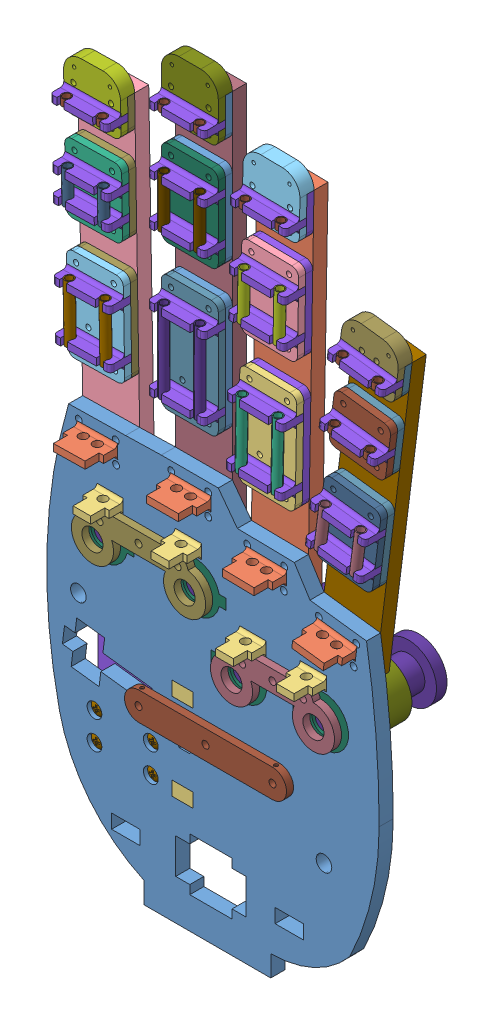
SolidWorks assembly palmUpComplete_Whiffletree, configuration Default. Lengths in mm.
Overall size (100.53 213.84 40.29).
205 component instances, 52 part files, 124 mates.
Components (placement in the parent):
- palmUp-1: palmUp [Default] at (29.1174 30.4931 80.2216) size (94.52 113.2 4)
- driverBaseFrame1-1: driverBaseFrame1 [Default] at (-2.9175 115.1932 80.2216) x (0.999847 0.017467 0) z (0.017467 -0.999847 0) size (11.5 12 4)
- driverBaseFrame1-2: driverBaseFrame1 [Default] at (23.5924 115.6931 80.2216) x (1 0 0) z (0 -1 0) size (11.5 12 4)
- driverBaseFrame1-3: driverBaseFrame1 [Default] at (45.1535 108.3901 80.2216) x (0.999848 -0.017452 0) z (-0.017452 -0.999848 0) size (11.5 12 4)
- driverBaseFrame1-4: driverBaseFrame1 [Default] at (65.1211 100.8452 80.2216) x (0.992117 -0.125312 0) z (-0.125312 -0.992117 0) size (11.5 12 4)
- driverBaseFrame2-1: driverBaseFrame2 [Default] at (-1948.2383 102.6443 -1374.6625) x (1 0 0) z (0 -1 0) size (7.5 12 4)
- driverBaseFrame2-2: driverBaseFrame2 [Default] at (1983.3157 100.6443 -1374.6625) x (-1 0 0) z (0 1 0) size (7.5 12 4)
- driverBaseFrame2-4: driverBaseFrame2 [Default] at (-1907.6963 87.8147 -1374.6625) x (1 0 0) z (0 -1 0) size (7.5 12 4)
- driverBaseFrame2-5: driverBaseFrame2 [Default] at (-1890.412 87.8147 -1374.6625) x (1 0 0) z (0 -1 0) size (7.5 12 4)
- index-1: index [Default] at (-52.494 173.2306 -0.0096) x (-0.999847 -0.017467 0) z (0 0 -1) size (16.2 99.16 12.01)
  - indexElastomer-1: indexElastomer [Default] at (-62.4059 -67.241 -80.2312) size (16.2 94.16 4)
  - indexPIP-1: indexPIP [Default] at (-62.4059 -42.8945 -84.2312) size (16.2 26.26 2)
  - indexMIP-1: indexMIP [Default] at (-62.4059 -8.6345 -84.2312) size (16.2 19.45 2)
  - indexDIP-1: indexDIP [Default] at (-62.4059 16.8205 -84.2312) size (16.2 14.95 4)
  - tubeDriver-6: tubeDriver [Default] at (-62.4059 20.8205 -80.2312) x (1 0 0) z (0 1 0) size (16.2 6 4)
  - tubeDriver-7: tubeDriver [Default] at (-62.4059 3.8205 -80.2312) x (1 0 0) z (0 1 0) size (16.2 6 4)
  - tubeDriver-8: tubeDriver [Default] at (-62.4059 -3.6345 -80.2312) x (1 0 0) z (0 1 0) size (16.2 6 4)
  - tubeDriver-9: tubeDriver [Default] at (-62.4059 -23.6345 -80.2312) x (1 0 0) z (0 1 0) size (16.2 6 4)
  - tubeDriver-10: tubeDriver [Default] at (-62.4059 -37.8945 -80.2312) x (1 0 0) z (0 1 0) size (16.2 6 4)
  - indexTube1-1: indexTube1 [Default] at (-49.2059 -21.6345 -86.4812) x (-0.964902 0 0.26261) z (0 -1 0) size (2.5 2.5 16.26)
  - indexTube1-2: indexTube1 [Default] at (-59.4059 -21.6345 -86.4812) x (-0.775159 0 0.631766) z (0 -1 0) size (2.5 2.5 16.26)
  - indexTube2-1: indexTube2 [Default] at (-49.2059 5.8205 -86.4812) x (0.360054 0 0.932932) z (0 -1 0) size (2.5 2.5 9.46)
  - indexTube2-2: indexTube2 [Default] at (-59.4059 5.8205 -86.4812) x (-0.658969 0 -0.75217) z (0 -1 0) size (2.5 2.5 9.46)
  - commonFingersTube-1: commonFingersTube [Default] at (-49.2059 22.8205 -86.4812) x (-0.856421 0 0.516277) z (0 -1 0) size (2.5 2.5 2)
  - commonFingersTube-2: commonFingersTube [Default] at (-59.4059 22.8205 -86.4812) x (-0.999231 0 0.039215) z (0 -1 0) size (2.5 2.5 2)
  - indexJointBase-1: indexJointBase [Default] at (-62.4059 -67.241 -82.2312) size (16.2 69.66 2)
- middle-1: middle [Default] at (34.8412 175.8995 -30.6566) size (16.2 113.14 12)
  - middleElastomer-1: middleElastomer [Default] at (-13.8237 -68.7065 106.8781) size (16.2 108.14 4)
  - middlePIP-1: middlePIP [Default] at (-13.8237 -44.2065 110.8781) size (16.2 33.21 2)
  - middleMIP-1: middleMIP [Default] at (-13.8237 -2.9965 110.8781) size (16.2 24.45 2)
  - middleDIP-1: middleDIP [Default] at (-5.7237 27.4535 110.8781) size (16.2 16.98 4)
  - tubeDriver-2: tubeDriver [Default] at (-13.8237 33.4535 110.8781) x (1 0 0) z (0 -1 0) size (16.2 6 4)
  - tubeDriver-3: tubeDriver [Default] at (-13.8237 16.4535 110.8781) x (1 0 0) z (0 -1 0) size (16.2 6 4)
  - tubeDriver-4: tubeDriver [Default] at (-13.8237 4.0035 110.8781) x (1 0 0) z (0 -1 0) size (16.2 6 4)
  - tubeDriver-5: tubeDriver [Default] at (-13.8237 -15.9965 110.8781) x (1 0 0) z (0 -1 0) size (16.2 6 4)
  - tubeDriver-6: tubeDriver [Default] at (-13.8237 -37.2065 110.8781) x (1 0 0) z (0 -1 0) size (16.2 6 4)
  - middleTube1-1: middleTube1 [Default] at (-10.8237 -39.2065 117.1281) x (1 0 0) z (0 1 0) size (2.5 2.5 23.21)
  - middleTube1-2: middleTube1 [Default] at (-0.6237 -39.2065 117.1281) x (1 0 0) z (0 1 0) size (2.5 2.5 23.21)
  - middleTube2-1: middleTube2 [Default] at (-10.8237 2.0035 117.1281) x (1 0 0) z (0 1 0) size (2.5 2.5 14.45)
  - middleTube2-2: middleTube2 [Default] at (-0.6237 2.0035 117.1281) x (1 0 0) z (0 1 0) size (2.5 2.5 14.45)
  - commonFingersTube-1: commonFingersTube [Default] at (-10.8237 31.4535 117.1281) x (1 0 0) z (0 1 0) size (2.5 2.5 2)
  - commonFingersTube-2: commonFingersTube [Default] at (-0.6237 31.4535 117.1281) x (1 0 0) z (0 1 0) size (2.5 2.5 2)
  - middleJointBase-1: middleJointBase [Default] at (-13.8237 -70.2065 110.8781) size (16.2 83.64 2)
- ring-1: ring [Default] at (23.5555 139.8292 -20.9472) x (-0.999848 0.017452 0) z (0 0 -1) size (16.2 107.96 12)
  - ringElastomer-1: ringElastomer [Default] at (-35.7683 -39.5573 -101.1688) size (16.2 102.96 4)
  - ringPIP-1: ringPIP [Default] at (-35.7683 -15.0573 -105.1688) size (16.2 29.14 2)
  - ringMIP-1: ringMIP [Default] at (-35.7683 22.0827 -105.1688) size (16.2 23.53 2)
  - ringDIP-1: ringDIP [Default] at (-19.5683 51.6077 -101.1688) x (-1 0 0) z (0 0 -1) size (16.2 16.8 4)
  - tubeDriver-6: tubeDriver [Default] at (-35.7683 55.6077 -101.1688) x (1 0 0) z (0 1 0) size (16.2 6 4)
  - tubeDriver-7: tubeDriver [Default] at (-35.7683 38.6077 -101.1688) x (1 0 0) z (0 1 0) size (16.2 6 4)
  - tubeDriver-8: tubeDriver [Default] at (-35.7683 27.0827 -101.1688) x (1 0 0) z (0 1 0) size (16.2 6 4)
  - tubeDriver-9: tubeDriver [Default] at (-35.7683 7.0827 -101.1688) x (1 0 0) z (0 1 0) size (16.2 6 4)
  - tubeDriver-10: tubeDriver [Default] at (-35.7683 -10.0573 -101.1688) x (1 0 0) z (0 1 0) size (16.2 6 4)
  - ringTube1-1: ringTube1 [Default] at (-22.5683 9.0827 -107.4188) x (1 0 0) z (0 -1 0) size (2.5 2.5 19.14)
  - ringTube1-2: ringTube1 [Default] at (-32.7683 9.0827 -107.4188) x (1 0 0) z (0 -1 0) size (2.5 2.5 19.14)
  - ringTube2-1: ringTube2 [Default] at (-22.5683 40.6077 -107.4188) x (1 0 0) z (0 -1 0) size (2.5 2.5 13.53)
  - ringTube2-2: ringTube2 [Default] at (-32.7683 40.6077 -107.4188) x (1 0 0) z (0 -1 0) size (2.5 2.5 13.53)
  - commonFingersTube-1: commonFingersTube [Default] at (-22.5683 57.6077 -107.4188) x (1 0 0) z (0 -1 0) size (2.5 2.5 2)
  - commonFingersTube-2: commonFingersTube [Default] at (-32.7683 57.6077 -107.4188) x (-0.448476 0 -0.893795) z (0 -1 0) size (2.5 2.5 2)
  - ringJointBase-1: ringJointBase [Default] at (-35.7683 -41.0573 -103.1688) size (16.2 78.46 2)
- pinky-1: pinky [Default] at (76.9532 164.3008 -0.0182) x (0.992117 -0.125312 0) z (0 0 1) size (16.2 89.09 12)
  - pinkyElastomer-1: pinkyElastomer [Default] at (-6.1366 -72.9381 76.2397) size (16.2 84.09 4)
  - pinkyPIP-1: pinkyPIP [Default] at (-6.1366 -48.4381 80.2397) size (16.2 21.74 2)
  - pinkyMIP-1: pinkyMIP [Default] at (-6.1366 -18.6981 80.2397) size (16.2 14.64 2)
  - pinkyDIP-1: pinkyDIP [Default] at (-6.1366 1.9469 80.2397) size (16.2 14.21 4)
  - tubeDriver-5: tubeDriver [Default] at (-6.1366 7.9469 80.2397) x (1 0 0) z (0 -1 0) size (16.2 6 4)
  - tubeDriver-7: tubeDriver [Default] at (-6.1366 -31.6981 80.2397) x (1 0 0) z (0 -1 0) size (16.2 6 4)
  - tubeDriver-8: tubeDriver [Default] at (-6.1366 -41.4381 80.2397) x (1 0 0) z (0 -1 0) size (16.2 6 4)
  - pinkyTube1-1: pinkyTube1 [Default] at (-3.1366 -43.4381 86.4897) x (1 0 0) z (0 1 0) size (2.5 2.5 11.74)
  - pinkyTube1-2: pinkyTube1 [Default] at (7.0634 -43.4381 86.4897) x (1 0 0) z (0 1 0) size (2.5 2.5 11.74)
  - tubeDriver-10: tubeDriver [Default] at (-6.1366 -10.3756 80.2397) x (1 0 0) z (0 -1 0) size (16.2 6 4)
  - commonFingersTube-1: commonFingersTube [Default] at (-3.1366 5.9469 86.4897) x (1 0 0) z (0 1 0) size (2.5 2.5 2)
  - commonFingersTube-2: commonFingersTube [Default] at (7.0634 5.9469 86.4897) x (1 0 0) z (0 1 0) size (2.5 2.5 2)
  - pinkyJointBase-1: pinkyJointBase [Default] at (-6.1366 -74.4381 80.2397) size (16.2 59.59 2)
  - commonFingersTube-3: commonFingersTube [Default] at (-3.1366 -12.3756 86.4897) x (1 0 0) z (0 1 0) size (2.5 2.5 2)
  - commonFingersTube-4: commonFingersTube [Default] at (7.0634 -12.3756 86.4897) x (1 0 0) z (0 1 0) size (2.5 2.5 2)
- buttonBase-1: buttonBase [Default] at (67.2648 77.3147 84.2216) x (0 -1 0) z (0 0 -1) size (16 16.84 9)
- buttonBase-2: buttonBase [Default] at (43.9805 77.3147 84.2216) x (0 -1 0) z (0 0 -1) size (16 16.84 9)
- buttonBase-3: buttonBase [Default] at (30.6388 92.1443 84.2216) x (0 1 0) z (0 0 -1) size (16 16.84 9)
- buttonBase-4: buttonBase [Default] at (4.4385 92.1443 84.2216) x (0 1 0) z (0 0 -1) size (16 16.84 9)
- buttonFrame-1: buttonFrame [Default] at (67.2648 77.3147 67.2216) x (-0.367754 -0.929923 0) z (0 0 1) size (16 16 8)
- buttonFrame-2: buttonFrame [Default] at (43.9805 77.3147 67.2216) x (-0.367754 -0.929923 0) z (0 0 1) size (16 16 8)
- buttonFrame-3: buttonFrame [Default] at (4.4385 92.1443 67.2216) x (-0.366273 -0.930508 0) z (0 0 1) size (16 16 8)
- buttonFrame-4: buttonFrame [Default] at (30.6388 92.1443 67.2216) x (-0.366273 -0.930508 0) z (0 0 1) size (16 16 8)
- buttonAxle-1: buttonAxle [Default] at (67.2648 77.3147 57.2216) size (16 16 27)
- buttonAxle-2: buttonAxle [Default] at (4.4385 92.1443 57.2216) size (16 16 27)
- buttonAxle-3: buttonAxle [Default] at (43.9805 77.3147 57.2216) x (-1 0 0) z (0 0 1) size (16 16 27)
- buttonAxle-4: buttonAxle [Default] at (30.6388 92.1443 57.2216) x (-1 0 0) z (0 0 1) size (16 16 27)
- parallel pin hardened_din-1: parallel pin hardened_din [Parallel Pin ISO 8734 - 2 x 14 - A - St] at (67.5898 69.8147 71.2178) x (0 1 0) z (-0.989175 0 -0.14674) size (14 2 2)
- parallel pin hardened_din-2: parallel pin hardened_din [Parallel Pin ISO 8734 - 2 x 14 - A - St] at (43.6555 69.8147 71.2178) x (0 1 0) z (-0.930242 0 0.366947) size (14 2 2)
- parallel pin hardened_din-3: parallel pin hardened_din [Parallel Pin ISO 8734 - 2 x 14 - A - St] at (4.7635 98.6443 71.2178) x (0 -1 0) z (0 0 1) size (14 2 2)
- parallel pin hardened_din-4: parallel pin hardened_din [Parallel Pin ISO 8734 - 2 x 14 - A - St] at (30.3138 98.6443 71.2178) x (0 -1 0) z (-0.297916 0 0.954592) size (14 2 2)
- Assem1-1: Assem1 [Default] at (68.1098 77.3321 69.8525) x (0.982823 0 0.184551) z (0 -1 0) size (9.07 23.24 9)
  - Spring Part-1: Spring Part [Default] at origin size (9 1 4.5)
  - Spring Part-7: Spring Part [Default] at (-0.0474 0.6138 0) x (0.988155 0.15346 0) z (0 0 -1) size (9 1 4.5)
  - Spring Part-8: Spring Part [Default] at (-0.0474 1.8415 0) x (0.988155 -0.15346 0) z (0 0 1) size (9 1 4.5)
  - Spring Part-9: Spring Part [Default] at (-0.0474 3.0692 0) x (0.988155 0.15346 0) z (0 0 -1) size (9 1 4.5)
  - Spring Part-10: Spring Part [Default] at (-0.0474 4.2969 0) x (0.988155 -0.15346 0) z (0 0 1) size (9 1 4.5)
  - Spring Part-11: Spring Part [Default] at (-0.0474 5.5246 0) x (0.988155 0.15346 0) z (0 0 -1) size (9 1 4.5)
  - Spring Part-12: Spring Part [Default] at (-0.0474 6.7522 0) x (0.988155 -0.15346 0) z (0 0 1) size (9 1 4.5) (hidden)
  - Spring Part-13: Spring Part [Default] at (-0.0474 7.9799 0) x (0.988155 0.15346 0) z (0 0 -1) size (9 1 4.5) (hidden)
  - Spring Part-14: Spring Part [Default] at (-0.0474 9.2076 0) x (0.988155 -0.15346 0) z (0 0 1) size (9 1 4.5) (hidden)
  - Spring Part-15: Spring Part [Default] at (-0.0474 10.4353 0) x (0.988155 0.15346 0) z (0 0 -1) size (9 1 4.5) (hidden)
  - Spring Part-16: Spring Part [Default] at (-0.0474 11.663 0) x (0.988155 -0.15346 0) z (0 0 1) size (9 1 4.5) (hidden)
  - Spring Part-17: Spring Part [Default] at (-0.0474 12.8906 0) x (0.988155 0.15346 0) z (0 0 -1) size (9 1 4.5) (hidden)
  - Spring Part-18: Spring Part [Default] at (-0.0474 14.1183 0) x (0.988155 -0.15346 0) z (0 0 1) size (9 1 4.5) (hidden)
  - Spring Part-19: Spring Part [Default] at (-0.0474 15.346 0) x (0.988155 0.15346 0) z (0 0 -1) size (9 1 4.5) (hidden)
  - Spring Part-20: Spring Part [Default] at (-0.0474 16.5737 0) x (0.988155 -0.15346 0) z (0 0 1) size (9 1 4.5) (hidden)
  - Spring Part-21: Spring Part [Default] at (-0.0474 17.8013 0) x (0.988155 0.15346 0) z (0 0 -1) size (9 1 4.5) (hidden)
  - Spring Part-22: Spring Part [Default] at (-0.0474 19.029 0) x (0.988155 -0.15346 0) z (0 0 1) size (9 1 4.5) (hidden)
  - Spring Part-23: Spring Part [Default] at (-0.0474 20.2567 0) x (0.988155 0.15346 0) z (0 0 -1) size (9 1 4.5) (hidden)
  - Spring Part-24: Spring Part [Default] at (-0.0474 21.4844 0) x (0.988155 -0.15346 0) z (0 0 1) size (9 1 4.5) (hidden)
  - Spring Part-25: Spring Part [Default] at (0 22.0982 0) x (1 0 0) z (0 0 -1) size (9 1 4.5) (hidden)
- Assem1-2: Assem1 [Default] at (43.2323 76.9505 75.7945) x (0.961864 0.191525 0.195284) z (-0.195284 0.980747 0) size (9.07 23.24 9)
  - Spring Part-1: Spring Part [Default] at origin size (9 1 4.5)
  - Spring Part-7: Spring Part [Default] at (-0.0474 0.6138 0) x (0.988155 0.15346 0) z (0 0 -1) size (9 1 4.5)
  - Spring Part-8: Spring Part [Default] at (-0.0474 1.8415 0) x (0.988155 -0.15346 0) z (0 0 1) size (9 1 4.5)
  - Spring Part-9: Spring Part [Default] at (-0.0474 3.0692 0) x (0.988155 0.15346 0) z (0 0 -1) size (9 1 4.5)
  - Spring Part-10: Spring Part [Default] at (-0.0474 4.2969 0) x (0.988155 -0.15346 0) z (0 0 1) size (9 1 4.5)
  - Spring Part-11: Spring Part [Default] at (-0.0474 5.5246 0) x (0.988155 0.15346 0) z (0 0 -1) size (9 1 4.5)
  - Spring Part-12: Spring Part [Default] at (-0.0474 6.7522 0) x (0.988155 -0.15346 0) z (0 0 1) size (9 1 4.5) (hidden)
  - Spring Part-13: Spring Part [Default] at (-0.0474 7.9799 0) x (0.988155 0.15346 0) z (0 0 -1) size (9 1 4.5) (hidden)
  - Spring Part-14: Spring Part [Default] at (-0.0474 9.2076 0) x (0.988155 -0.15346 0) z (0 0 1) size (9 1 4.5) (hidden)
  - Spring Part-15: Spring Part [Default] at (-0.0474 10.4353 0) x (0.988155 0.15346 0) z (0 0 -1) size (9 1 4.5) (hidden)
  - Spring Part-16: Spring Part [Default] at (-0.0474 11.663 0) x (0.988155 -0.15346 0) z (0 0 1) size (9 1 4.5) (hidden)
  - Spring Part-17: Spring Part [Default] at (-0.0474 12.8906 0) x (0.988155 0.15346 0) z (0 0 -1) size (9 1 4.5) (hidden)
  - Spring Part-18: Spring Part [Default] at (-0.0474 14.1183 0) x (0.988155 -0.15346 0) z (0 0 1) size (9 1 4.5) (hidden)
  - Spring Part-19: Spring Part [Default] at (-0.0474 15.346 0) x (0.988155 0.15346 0) z (0 0 -1) size (9 1 4.5) (hidden)
  - Spring Part-20: Spring Part [Default] at (-0.0474 16.5737 0) x (0.988155 -0.15346 0) z (0 0 1) size (9 1 4.5) (hidden)
  - Spring Part-21: Spring Part [Default] at (-0.0474 17.8013 0) x (0.988155 0.15346 0) z (0 0 -1) size (9 1 4.5) (hidden)
  - Spring Part-22: Spring Part [Default] at (-0.0474 19.029 0) x (0.988155 -0.15346 0) z (0 0 1) size (9 1 4.5) (hidden)
  - Spring Part-23: Spring Part [Default] at (-0.0474 20.2567 0) x (0.988155 0.15346 0) z (0 0 -1) size (9 1 4.5) (hidden)
  - Spring Part-24: Spring Part [Default] at (-0.0474 21.4844 0) x (0.988155 -0.15346 0) z (0 0 1) size (9 1 4.5) (hidden)
  - Spring Part-25: Spring Part [Default] at (0 22.0982 0) x (1 0 0) z (0 0 -1) size (9 1 4.5) (hidden)
- Assem1-3: Assem1 [Default] at (30.4884 91.6348 76.0217) x (1 0 0) z (0 1 0) size (9.07 23.24 9)
  - Spring Part-1: Spring Part [Default] at origin size (9 1 4.5)
  - Spring Part-7: Spring Part [Default] at (-0.0474 0.6138 0) x (0.988155 0.15346 0) z (0 0 -1) size (9 1 4.5)
  - Spring Part-8: Spring Part [Default] at (-0.0474 1.8415 0) x (0.988155 -0.15346 0) z (0 0 1) size (9 1 4.5)
  - Spring Part-9: Spring Part [Default] at (-0.0474 3.0692 0) x (0.988155 0.15346 0) z (0 0 -1) size (9 1 4.5)
  - Spring Part-10: Spring Part [Default] at (-0.0474 4.2969 0) x (0.988155 -0.15346 0) z (0 0 1) size (9 1 4.5)
  - Spring Part-11: Spring Part [Default] at (-0.0474 5.5246 0) x (0.988155 0.15346 0) z (0 0 -1) size (9 1 4.5)
  - Spring Part-12: Spring Part [Default] at (-0.0474 6.7522 0) x (0.988155 -0.15346 0) z (0 0 1) size (9 1 4.5) (hidden)
  - Spring Part-13: Spring Part [Default] at (-0.0474 7.9799 0) x (0.988155 0.15346 0) z (0 0 -1) size (9 1 4.5) (hidden)
  - Spring Part-14: Spring Part [Default] at (-0.0474 9.2076 0) x (0.988155 -0.15346 0) z (0 0 1) size (9 1 4.5) (hidden)
  - Spring Part-15: Spring Part [Default] at (-0.0474 10.4353 0) x (0.988155 0.15346 0) z (0 0 -1) size (9 1 4.5) (hidden)
  - Spring Part-16: Spring Part [Default] at (-0.0474 11.663 0) x (0.988155 -0.15346 0) z (0 0 1) size (9 1 4.5) (hidden)
  - Spring Part-17: Spring Part [Default] at (-0.0474 12.8906 0) x (0.988155 0.15346 0) z (0 0 -1) size (9 1 4.5) (hidden)
  - Spring Part-18: Spring Part [Default] at (-0.0474 14.1183 0) x (0.988155 -0.15346 0) z (0 0 1) size (9 1 4.5) (hidden)
  - Spring Part-19: Spring Part [Default] at (-0.0474 15.346 0) x (0.988155 0.15346 0) z (0 0 -1) size (9 1 4.5) (hidden)
  - Spring Part-20: Spring Part [Default] at (-0.0474 16.5737 0) x (0.988155 -0.15346 0) z (0 0 1) size (9 1 4.5) (hidden)
  - Spring Part-21: Spring Part [Default] at (-0.0474 17.8013 0) x (0.988155 0.15346 0) z (0 0 -1) size (9 1 4.5) (hidden)
  - Spring Part-22: Spring Part [Default] at (-0.0474 19.029 0) x (0.988155 -0.15346 0) z (0 0 1) size (9 1 4.5) (hidden)
  - Spring Part-23: Spring Part [Default] at (-0.0474 20.2567 0) x (0.988155 0.15346 0) z (0 0 -1) size (9 1 4.5) (hidden)
  - Spring Part-24: Spring Part [Default] at (-0.0474 21.4844 0) x (0.988155 -0.15346 0) z (0 0 1) size (9 1 4.5) (hidden)
  - Spring Part-25: Spring Part [Default] at (0 22.0982 0) x (1 0 0) z (0 0 -1) size (9 1 4.5) (hidden)
- Assem1-4: Assem1 [Default] at (3.643 90.6443 75.9726) x (1 0 0) z (0 1 0) size (9.07 23.24 9)
  - Spring Part-1: Spring Part [Default] at origin size (9 1 4.5)
  - Spring Part-7: Spring Part [Default] at (-0.0474 0.6138 0) x (0.988155 0.15346 0) z (0 0 -1) size (9 1 4.5)
  - Spring Part-8: Spring Part [Default] at (-0.0474 1.8415 0) x (0.988155 -0.15346 0) z (0 0 1) size (9 1 4.5)
  - Spring Part-9: Spring Part [Default] at (-0.0474 3.0692 0) x (0.988155 0.15346 0) z (0 0 -1) size (9 1 4.5)
  - Spring Part-10: Spring Part [Default] at (-0.0474 4.2969 0) x (0.988155 -0.15346 0) z (0 0 1) size (9 1 4.5)
  - Spring Part-11: Spring Part [Default] at (-0.0474 5.5246 0) x (0.988155 0.15346 0) z (0 0 -1) size (9 1 4.5)
  - Spring Part-12: Spring Part [Default] at (-0.0474 6.7522 0) x (0.988155 -0.15346 0) z (0 0 1) size (9 1 4.5) (hidden)
  - Spring Part-13: Spring Part [Default] at (-0.0474 7.9799 0) x (0.988155 0.15346 0) z (0 0 -1) size (9 1 4.5) (hidden)
  - Spring Part-14: Spring Part [Default] at (-0.0474 9.2076 0) x (0.988155 -0.15346 0) z (0 0 1) size (9 1 4.5) (hidden)
  - Spring Part-15: Spring Part [Default] at (-0.0474 10.4353 0) x (0.988155 0.15346 0) z (0 0 -1) size (9 1 4.5) (hidden)
  - Spring Part-16: Spring Part [Default] at (-0.0474 11.663 0) x (0.988155 -0.15346 0) z (0 0 1) size (9 1 4.5) (hidden)
  - Spring Part-17: Spring Part [Default] at (-0.0474 12.8906 0) x (0.988155 0.15346 0) z (0 0 -1) size (9 1 4.5) (hidden)
  - Spring Part-18: Spring Part [Default] at (-0.0474 14.1183 0) x (0.988155 -0.15346 0) z (0 0 1) size (9 1 4.5) (hidden)
  - Spring Part-19: Spring Part [Default] at (-0.0474 15.346 0) x (0.988155 0.15346 0) z (0 0 -1) size (9 1 4.5) (hidden)
  - Spring Part-20: Spring Part [Default] at (-0.0474 16.5737 0) x (0.988155 -0.15346 0) z (0 0 1) size (9 1 4.5) (hidden)
  - Spring Part-21: Spring Part [Default] at (-0.0474 17.8013 0) x (0.988155 0.15346 0) z (0 0 -1) size (9 1 4.5) (hidden)
  - Spring Part-22: Spring Part [Default] at (-0.0474 19.029 0) x (0.988155 -0.15346 0) z (0 0 1) size (9 1 4.5) (hidden)
  - Spring Part-23: Spring Part [Default] at (-0.0474 20.2567 0) x (0.988155 0.15346 0) z (0 0 -1) size (9 1 4.5) (hidden)
  - Spring Part-24: Spring Part [Default] at (-0.0474 21.4844 0) x (0.988155 -0.15346 0) z (0 0 1) size (9 1 4.5) (hidden)
  - Spring Part-25: Spring Part [Default] at (0 22.0982 0) x (1 0 0) z (0 0 -1) size (9 1 4.5) (hidden)
- SupportPulleyPalmUpAssem-1: SupportPulleyPalmUpAssem [Default] at (18.0404 39.4745 49.5054) size (10 28.63 11.6)
  - supportPulleyPalmUp2-1: supportPulleyPalmUp2 [Default] at (10.0404 13.9256 23.1162) size (7.5 28.63 2)
  - supportPulleyPalmUp-1: supportPulleyPalmUp [Default] at (12.0404 26.3656 34.7162) x (-1 0 0) z (0 -1 0) size (10 11.6 4)
  - supportPulleyPalmUp-2: supportPulleyPalmUp [Default] at (12.0404 1.7356 34.7162) x (-1 0 0) z (0 -1 0) size (10 11.6 4)
- hex nut style 1 gradeab_din-1: hex nut style 1 gradeab_din [Hexagon Nut ISO 4032 - M3 - D - S] at (27.442 52.7975 82.6216) x (0 1 0) z (0 0 1) size (5.5 6.35 2.4)
- plain washer 6902 type abc_din-1: plain washer 6902 type abc_din [DIN 6902-C3.2] at (28.0808 53.4001 80.2216) x (0 0 -1) z (0.195239 0.980756 0) size (0.8 7 7)
- pulley-1: pulley [Default] at (28.0808 53.4001 75.4216) x (0.991013 -0.133768 0) z (0 0 1) size (12 12 4)
- plain washer 6902 type abc_din-2: plain washer 6902 type abc_din [DIN 6902-C3.2] at (28.0808 53.4001 75.4216) x (0 0 -1) z (0.978291 0.207235 0) size (0.8 7 7)
- socket head cap screw 4762_din-1: socket head cap screw 4762_din [ISO 4762 M3 x 10 --- 10S] at (28.0808 53.4001 69.6216) x (0 0 1) z (-0.999894 -0.01457 0) size (13 5.5 5.5)
- baseHerkulex-1: baseHerkulex [Default] at (-4.9352 30.4931 70.2216) size (31 58.5 17.5)
- pan head cross recess screw_din-1: pan head cross recess screw_din [ISO 7045 - M2 x 10 - Z --- 10S] at (18.0174 47.3687 83.8216) x (0 0 -1) z (0.086476 0.996254 0) size (11.57 4 4)
- pan head cross recess screw_din-2: pan head cross recess screw_din [ISO 7045 - M2 x 10 - Z --- 10S] at (18.0174 39.3687 83.8216) x (0 0 -1) z (-0.029913 -0.999553 0) size (11.57 4 4)
- pan head cross recess screw_din-3: pan head cross recess screw_din [ISO 7045 - M2 x 10 - Z --- 10S] at (2.0174 39.3687 83.8216) x (0 0 -1) z (1 0 0) size (11.57 4 4)
- pan head cross recess screw_din-4: pan head cross recess screw_din [ISO 7045 - M2 x 10 - Z --- 10S] at (2.0174 47.3687 83.8216) x (0 0 -1) z (1 0 0) size (11.57 4 4)
- hex nut style 1 gradeab_din-2: hex nut style 1 gradeab_din [Hexagon Nut ISO 4032 - M2 - D - S] at (2.0174 39.3687 72.2216) x (0.792425 -0.60997 0) z (0 0 1) size (4 4.62 1.6)
- hex nut style 1 gradeab_din-3: hex nut style 1 gradeab_din [Hexagon Nut ISO 4032 - M2 - D - S] at (18.0174 47.3687 72.2216) x (0.098807 -0.995107 0) z (0 0 1) size (4 4.62 1.6)
- hex nut style 1 gradeab_din-4: hex nut style 1 gradeab_din [Hexagon Nut ISO 4032 - M2 - D - S] at (2.0174 47.3687 72.2216) size (4 4.62 1.6)
- hex nut style 1 gradeab_din-5: hex nut style 1 gradeab_din [Hexagon Nut ISO 4032 - M2 - D - S] at (18.0174 39.3687 72.2216) size (4 4.62 1.6)
- plasticSpacer-1: plasticSpacer [Default] at (2.0174 47.3687 76.2216) size (6 6 4)
- plasticSpacer-2: plasticSpacer [Default] at (18.0174 47.3687 76.2216) size (6 6 4)
- plasticSpacer-3: plasticSpacer [Default] at (18.0174 39.3687 76.2216) x (0.106039 0.994362 0) z (0 0 1) size (6 6 4)
- plasticSpacer-4: plasticSpacer [Default] at (2.0174 39.3687 76.2216) x (0.99764 -0.068656 0) z (0 0 1) size (6 6 4)
- whiffleetree-1: whiffleetree [Default] at (16.2286 39.1819 47.2015) x (1 0.000009 0) z (0 0 1) size (74.83 77 2)
  - mainBar-1: mainBar [Default] at (20.3524 18.4625 38.0201) size (46.08 8 2)
  - dynema1-1: dynema1 [Default] at (1.3104 55.9625 39.0201) x (0.250397 0 -0.968143) z (0 -1 0) size (1 1 34) (hidden)
  - barIndexMiddle-1: barIndexMiddle [Default] at (1.3104 58.4625 38.0201) size (38.2 14.5 2)
  - dynema2-1: dynema2 [Default] at (39.3944 21.9625 39.0201) x (0.365635 0 0.930758) z (0 1 0) size (1 1 19.17) (hidden)
  - barMiddlePinky-1: barMiddlePinky [Default] at (39.3944 43.6325 38.0201) size (35.28 14.5 2)
  - dynema3-1: dynema3 [Default] at (20.3524 14.9625 39.0201) x (0.922872 0 -0.385106) z (0 -1 0) size (1 1 30.5) (hidden)
Mates (geometry in assembly coordinates):
- Coincident1: coincident anti-aligned: plane of palmUp-1 through (-1.6321 113.2154 84.2216) normal (-0.017467 0.999847 0); plane of driverBaseFrame1-1 through (-2.8826 113.1935 80.2216) normal (0.017467 -0.999847 0)
- Coincident2: coincident anti-aligned: plane of palmUp-1 through (7.3666 113.3726 84.2216) normal (-0.999847 -0.017467 0); plane of driverBaseFrame1-1 through (7.3666 113.3726 84.2216) normal (0.999847 0.017467 0)
- Coincident3: coincident aligned: plane of palmUp-1 through (143.3195 75.6611 80.2216) normal (0 0 -1); plane of driverBaseFrame1-1 through (-1.6328 113.2154 80.2216) normal (0 0 -1)
- Coincident4: coincident anti-aligned: plane of palmUp-1 through (24.8424 113.6931 84.2216) normal (0 1 0); plane of driverBaseFrame1-2 through (23.5924 113.6931 80.2216) normal (0 -1 0)
- Coincident5: coincident anti-aligned: plane of palmUp-1 through (24.8424 115.6931 84.2216) normal (1 0 0); plane of driverBaseFrame1-2 through (24.8424 113.6931 84.2216) normal (-1 0 0)
- Coincident6: coincident aligned: plane of palmUp-1 through (143.3195 75.6611 80.2216) normal (0 0 -1); plane of driverBaseFrame1-2 through (24.8424 113.6931 80.2216) normal (0 0 -1)
- Coincident7: coincident aligned: plane of palmUp-1 through (143.3195 75.6611 80.2216) normal (0 0 -1); plane of driverBaseFrame1-3 through (46.3684 106.3686 80.2216) normal (0 0 -1)
- Coincident8: coincident anti-aligned: plane of palmUp-1 through (54.952 108.2191 84.2216) normal (-0.017452 -0.999848 0); plane of driverBaseFrame1-3 through (45.1535 108.3901 80.2216) normal (0.017452 0.999848 0)
- Coincident12: coincident anti-aligned: plane of palmUp-1 through (46.4033 108.3683 84.2216) normal (0.999848 -0.017452 0); plane of driverBaseFrame1-3 through (46.3684 106.3686 84.2216) normal (-0.999848 0.017452 0)
- Coincident13: coincident anti-aligned: plane of palmUp-1 through (66.1107 98.7043 84.2216) normal (0.125312 0.992117 0); plane of driverBaseFrame1-4 through (64.8705 98.861 80.2216) normal (-0.125312 -0.992117 0)
- Coincident14: coincident aligned: plane of palmUp-1 through (143.3195 75.6611 80.2216) normal (0 0 -1); plane of driverBaseFrame1-4 through (66.1107 98.7043 80.2216) normal (0 0 -1)
- Coincident15: coincident anti-aligned: plane of palmUp-1 through (66.3613 100.6886 84.2216) normal (0.992117 -0.125312 0); plane of driverBaseFrame1-4 through (66.1107 98.7043 84.2216) normal (-0.992117 0.125312 0)
- Coincident16: coincident anti-aligned: plane of palmUp-1 through (3.9385 100.6443 84.2216) normal (0 1 0); plane of driverBaseFrame2-1 through (-1948.2383 100.6443 -1374.6625) normal (0 -1 0)
- Coincident17: coincident aligned: plane of palmUp-1 through (143.3195 75.6611 80.2216) normal (0 0 -1); plane of driverBaseFrame2-1 through (3.9385 100.6443 80.2216) normal (0 0 -1)
- Coincident18: coincident anti-aligned: plane of palmUp-1 through (3.9385 102.6443 84.2216) normal (1 0 0); plane of driverBaseFrame2-1 through (3.9385 100.6443 84.2216) normal (-1 0 0)
- Distance1: distance = 0 mm aligned: plane of palmUp-1 through (143.3195 75.6611 80.2216) normal (0 0 -1); plane of driverBaseFrame2-2 through (31.1388 102.6443 80.2216) normal (0 0 -1)
- Coincident20: coincident anti-aligned: plane of palmUp-1 through (31.1388 100.6443 84.2216) normal (-1 0 0); plane of driverBaseFrame2-2 through (31.1388 102.6443 84.2216) normal (1 0 0)
- Coincident21: coincident anti-aligned: plane of palmUp-1 through (26.1388 102.6443 84.2216) normal (0 -1 0); plane of driverBaseFrame2-2 through (1983.3157 102.6443 -1374.6625) normal (0 1 0)
- Coincident22: coincident anti-aligned: plane of palmUp-1 through (44.4805 85.8147 84.2216) normal (0 1 0); plane of driverBaseFrame2-4 through (-1907.6963 85.8147 -1374.6625) normal (0 -1 0)
- Coincident23: coincident aligned: plane of palmUp-1 through (143.3195 75.6611 80.2216) normal (0 0 -1); plane of driverBaseFrame2-4 through (44.4805 85.8147 80.2216) normal (0 0 -1)
- Coincident24: coincident anti-aligned: plane of palmUp-1 through (49.4805 85.8147 84.2216) normal (-1 0 0); plane of driverBaseFrame2-4 through (49.4805 85.8147 84.2216) normal (1 0 0)
- Coincident25: coincident anti-aligned: plane of palmUp-1 through (61.7648 85.8147 84.2216) normal (0 1 0); plane of driverBaseFrame2-5 through (-1890.412 85.8147 -1374.6625) normal (0 -1 0)
- Coincident26: coincident aligned: plane of palmUp-1 through (143.3195 75.6611 80.2216) normal (0 0 -1); plane of driverBaseFrame2-5 through (61.7648 85.8147 80.2216) normal (0 0 -1)
- Coincident27: coincident anti-aligned: plane of palmUp-1 through (61.7648 87.8147 84.2216) normal (1 0 0); plane of driverBaseFrame2-5 through (61.7648 85.8147 84.2216) normal (-1 0 0)
- Concentric1: concentric anti-aligned: cylinder of palmUp-1 through (8.0553 116.8851 84.2216) axis (0 0 -1) radius 0.975; cylinder of index-1/indexElastomer-1 through (8.0553 116.8851 76.2216) axis (0 0 1) radius 0.5
- Concentric2: concentric anti-aligned: cylinder of palmUp-1 through (8.1601 110.886 84.2216) axis (0 0 -1) radius 0.975; cylinder of index-1/indexElastomer-1 through (8.1601 110.886 76.2216) axis (0 0 1) radius 0.5
- Coincident28: coincident anti-aligned: plane of palmUp-1 through (143.3195 75.6611 80.2216) normal (0 0 -1); plane of index-1/indexElastomer-1 through (11.0769 107.0899 80.2216) normal (0 0 1)
- Concentric3: concentric aligned: cylinder of palmUp-1 through (23.8674 111.1931 84.2216) axis (0 0 -1) radius 0.975; cylinder of middle-1/middleElastomer-1 through (23.8674 111.1931 80.2216) axis (0 0 -1) radius 0.52
- Concentric4: concentric aligned: circle of palmUp-1; circle of middle-1/middleElastomer-1
- Coincident29: coincident anti-aligned: plane of palmUp-1 through (143.3195 75.6611 80.2216) normal (0 0 -1); plane of middle-1/middleElastomer-1 through (21.0174 107.1931 80.2216) normal (0 0 1)
- Concentric5: concentric aligned: circle of palmUp-1; cylinder of ring-1/ringElastomer-1 through (45.3499 103.886 76.2216) axis (0 0 1) radius 0.5
- Concentric6: concentric anti-aligned: cylinder of palmUp-1 through (45.4546 109.8851 84.2216) axis (0 0 -1) radius 0.975; cylinder of ring-1/ringElastomer-1 through (45.4546 109.8851 76.2216) axis (0 0 1) radius 0.5
- Coincident30: coincident anti-aligned: plane of palmUp-1 through (143.3195 75.6611 80.2216) normal (0 0 -1); plane of ring-1/ringElastomer-1 through (58.628 99.6536 80.2216) normal (0 0 1)
- Concentric7: concentric aligned: cylinder of palmUp-1 through (65.0537 96.318 84.2216) axis (0 0 -1) radius 0.975; cylinder of pinky-1/pinkyElastomer-1 through (65.0537 96.318 80.2216) axis (0 0 -1) radius 0.52
- Concentric8: concentric anti-aligned: cylinder of palmUp-1 through (65.8055 102.2707 84.2216) axis (0 0 -1) radius 0.975; circle of pinky-1/pinkyElastomer-1
- Coincident31: coincident anti-aligned: plane of palmUp-1 through (143.3195 75.6611 80.2216) normal (0 0 -1); plane of pinky-1/pinkyElastomer-1 through (61.7249 92.7066 80.2216) normal (0 0 1)
- Concentric9: concentric anti-aligned: cylinder of palmUp-1 through (67.2648 77.3147 84.2216) axis (0 0 -1) radius 7; cylinder of buttonBase-1 through (67.2648 77.3147 80.2216) axis (0 0 1) radius 7
- Coincident32: coincident: moEndPointRef_w of palmUp-1; plane of buttonBase-1 through (60.4274 75.8147 80.2216) normal (0 -1 0)
- Coincident40: coincident anti-aligned: plane of palmUp-1 through (143.3195 75.6611 80.2216) normal (0 0 -1); plane of buttonBase-1 through (67.2648 77.3147 80.2216) normal (0 0 1)
- Concentric10: concentric anti-aligned: cylinder of palmUp-1 through (43.9805 77.3147 84.2216) axis (0 0 -1) radius 7; cylinder of buttonBase-2 through (43.9805 77.3147 80.2216) axis (0 0 1) radius 7
- Coincident34: coincident anti-aligned: plane of palmUp-1 through (35.1431 75.8147 84.2216) normal (0 1 0); plane of buttonBase-2 through (37.1431 75.8147 80.2216) normal (0 -1 0)
- Coincident41: coincident anti-aligned: plane of palmUp-1 through (143.3195 75.6611 80.2216) normal (0 0 -1); plane of buttonBase-2 through (43.9805 77.3147 80.2216) normal (0 0 1)
- Concentric11: concentric anti-aligned: cylinder of palmUp-1 through (30.6388 92.1443 84.2216) axis (0 0 -1) radius 7; cylinder of buttonBase-3 through (30.6388 92.1443 80.2216) axis (0 0 1) radius 7
- Coincident37: coincident anti-aligned: plane of palmUp-1 through (39.4762 90.6443 84.2216) normal (0 1 0); plane of buttonBase-3 through (38.497 90.6443 80.2216) normal (0 -1 0)
- Coincident42: coincident anti-aligned: plane of palmUp-1 through (143.3195 75.6611 80.2216) normal (0 0 -1); plane of buttonBase-3 through (30.6388 92.1443 80.2216) normal (0 0 1)
- Concentric13: concentric anti-aligned: cylinder of palmUp-1 through (4.4385 92.1443 84.2216) axis (0 0 -1) radius 7; cylinder of buttonBase-4 through (4.4385 92.1443 80.2216) axis (0 0 1) radius 7
- Coincident39: coincident anti-aligned: plane of palmUp-1 through (11.2759 93.6443 84.2216) normal (0 -1 0); plane of buttonBase-4 through (11.2759 93.6443 80.2216) normal (0 1 0)
- Coincident43: coincident anti-aligned: plane of palmUp-1 through (143.3195 75.6611 80.2216) normal (0 0 -1); plane of buttonBase-4 through (4.4385 92.1443 80.2216) normal (0 0 1)
- Concentric14: concentric anti-aligned: cylinder of buttonBase-1 through (67.2648 77.3147 75.2216) axis (0 0 1) radius 5; cylinder of buttonFrame-1 through (67.2648 77.3147 75.2216) axis (0 0 -1) radius 5
- Coincident44: coincident aligned: plane of buttonBase-1 through (63.4238 70.2971 76.2216) normal (0.877201 -0.480124 0); plane of buttonFrame-1 through (63.4238 70.2971 72.7216) normal (0.877201 -0.480124 0)
- Coincident60: coincident anti-aligned: plane of buttonBase-1 through (67.2648 77.3147 75.2216) normal (0 0 -1); plane of buttonFrame-1 through (67.2648 77.3147 75.2216) normal (0 0 1)
- Concentric15: concentric anti-aligned: cylinder of buttonBase-2 through (43.9805 77.3147 75.2216) axis (0 0 1) radius 5; cylinder of buttonFrame-2 through (43.9805 77.3147 75.2216) axis (0 0 -1) radius 5
- Coincident46: coincident: line of buttonBase-2 through (41.5799 72.9287 77.2216) axis (-0.480124 -0.877201 0); plane of buttonFrame-2 through (40.1395 70.2971 72.7216) normal (0.877201 -0.480124 0)
- Coincident61: coincident anti-aligned: plane of buttonBase-2 through (43.9805 77.3147 75.2216) normal (0 0 -1); plane of buttonFrame-2 through (43.9805 77.3147 75.2216) normal (0 0 1)
- Concentric16: concentric anti-aligned: cylinder of buttonBase-3 through (30.6388 92.1443 75.2216) axis (0 0 1) radius 5; cylinder of buttonFrame-4 through (30.6388 92.1443 75.2216) axis (0 0 -1) radius 5
- Parallel1: parallel aligned: plane of buttonBase-4 through (0.6087 85.1206 76.2216) normal (0.877964 -0.478727 0); plane of buttonFrame-4 through (26.809 85.1206 72.7216) normal (0.877964 -0.478727 0)
- Coincident63: coincident anti-aligned: plane of buttonBase-4 through (4.4385 92.1443 75.2216) normal (0 0 -1); plane of buttonFrame-4 through (30.6388 92.1443 75.2216) normal (0 0 1)
- Concentric17: concentric anti-aligned: cylinder of buttonBase-4 through (4.4385 92.1443 75.2216) axis (0 0 1) radius 5; cylinder of buttonFrame-3 through (4.4385 92.1443 75.2216) axis (0 0 -1) radius 5
- Coincident50: coincident aligned: plane of buttonBase-4 through (0.6087 85.1206 76.2216) normal (0.877964 -0.478727 0); plane of buttonFrame-3 through (0.6087 85.1206 72.7216) normal (0.877964 -0.478727 0)
- Coincident62: coincident anti-aligned: plane of buttonBase-4 through (4.4385 92.1443 75.2216) normal (0 0 -1); plane of buttonFrame-3 through (4.4385 92.1443 75.2216) normal (0 0 1)
- Concentric18: concentric aligned: cylinder of buttonFrame-1 through (67.2648 77.3147 75.2216) axis (0 0 -1) radius 5; cylinder of buttonAxle-1 through (67.2648 77.3147 74.2216) axis (0 0 -1) radius 4.675
- Distance6: distance = 7 mm anti-aligned: plane of buttonAxle-1 through (67.2648 77.3147 74.2216) normal (0 0 1); plane of buttonFrame-1 through (67.2648 77.3147 67.2216) normal (0 0 -1)
- Concentric19: concentric aligned: cylinder of buttonFrame-2 through (43.9805 77.3147 75.2216) axis (0 0 -1) radius 5; cylinder of buttonAxle-3 through (43.9805 77.3147 74.2216) axis (0 0 -1) radius 4.675
- Distance7: distance = 7 mm anti-aligned: plane of buttonFrame-2 through (43.9805 77.3147 67.2216) normal (0 0 -1); plane of buttonAxle-3 through (43.9805 77.3147 74.2216) normal (0 0 1)
- Concentric20: concentric aligned: cylinder of buttonFrame-4 through (30.6388 92.1443 75.2216) axis (0 0 -1) radius 5; cylinder of buttonAxle-4 through (30.6388 92.1443 74.2216) axis (0 0 -1) radius 4.675
- Distance8: distance = 7 mm anti-aligned: plane of buttonFrame-4 through (30.6388 92.1443 67.2216) normal (0 0 -1); plane of buttonAxle-4 through (30.6388 92.1443 74.2216) normal (0 0 1)
- Concentric21: concentric aligned: cylinder of buttonFrame-3 through (4.4385 92.1443 75.2216) axis (0 0 -1) radius 5; cylinder of buttonAxle-2 through (4.4385 92.1443 74.2216) axis (0 0 -1) radius 4.675
- Distance9: distance = 7 mm anti-aligned: plane of buttonFrame-3 through (4.4385 92.1443 67.2216) normal (0 0 -1); plane of buttonAxle-2 through (4.4385 92.1443 74.2216) normal (0 0 1)
- Concentric22: concentric anti-aligned: cylinder of buttonAxle-1 through (67.5898 69.8147 71.2178) axis (0 1 0) radius 1.225; cylinder of parallel pin hardened_din-1 through (67.5898 63.4647 71.2178) axis (0 -1 0) radius 1
- Distance10: distance = 6 mm aligned: plane of parallel pin hardened_din-1 through (67.7227 69.8147 70.3214) normal (0 -1 0); plane of buttonBase-1 through (60.4274 75.8147 80.2216) normal (0 -1 0)
- Concentric23: concentric aligned: cylinder of buttonAxle-3 through (43.6555 84.8147 71.2178) axis (0 -1 0) radius 1.225; cylinder of parallel pin hardened_din-2 through (43.6555 63.4647 71.2178) axis (0 -1 0) radius 1
- Distance11: distance = 8 mm anti-aligned: plane of parallel pin hardened_din-2 through (43.6555 83.8147 71.2178) normal (0 1 0); plane of buttonBase-2 through (37.1431 75.8147 80.2216) normal (0 -1 0)
- Concentric24: concentric anti-aligned: cylinder of buttonAxle-4 through (30.3138 99.6443 71.2178) axis (0 -1 0) radius 1.225; cylinder of parallel pin hardened_din-4 through (30.3138 104.9943 71.2178) axis (0 1 0) radius 1
- Distance12: distance = 6 mm aligned: plane of parallel pin hardened_din-4 through (30.3138 84.6443 71.2178) normal (0 -1 0); plane of buttonBase-3 through (38.497 90.6443 80.2216) normal (0 -1 0)
- Concentric25: concentric aligned: cylinder of buttonAxle-2 through (4.7635 84.6443 71.2178) axis (0 1 0) radius 1.225; cylinder of parallel pin hardened_din-3 through (4.7635 104.9943 71.2178) axis (0 1 0) radius 1
- Distance13: distance = 6 mm aligned: plane of parallel pin hardened_din-3 through (4.7635 84.6443 71.2178) normal (0 -1 0); plane of buttonBase-4 through (12.2966 90.6443 80.2216) normal (0 -1 0)
- Parallel2: parallel anti-aligned: plane of buttonBase-1 through (60.4274 75.8147 80.2216) normal (0 -1 0); plane of Assem1-1/Spring Part-11 through (70.8151 77.3321 76.6062) normal (0 1 0)
- Parallel3: parallel: line of buttonBase-2 through (36.1224 75.8147 75.2216) axis (0 0 1); plane of Assem1-2/Spring Part-1 through (47.0797 77.7166 76.5756) normal (-0.195284 0.980747 0)
- Parallel4: parallel anti-aligned: plane of buttonBase-3 through (38.497 90.6443 80.2216) normal (0 -1 0); plane of Assem1-3/Spring Part-1 through (34.4884 91.6348 76.0217) normal (0 1 0)
- Coincident59: coincident anti-aligned: plane of buttonBase-4 through (12.2966 90.6443 80.2216) normal (0 -1 0); plane of Assem1-4/Spring Part-1 through (7.643 90.6443 75.9726) normal (0 1 0)
- Coincident64: coincident anti-aligned: plane of palmUp-1 through (30.0808 37.2101 84.2216) normal (0 1 0); plane of SupportPulleyPalmUpAssem-1/supportPulleyPalmUp-2 through (30.0808 37.2101 84.2216) normal (0 -1 0)
- Coincident65: coincident anti-aligned: plane of palmUp-1 through (24.0808 37.2101 84.2216) normal (1 0 0); plane of SupportPulleyPalmUpAssem-1/supportPulleyPalmUp-2 through (24.0808 37.2101 84.2216) normal (-1 0 0)
- Coincident67: coincident anti-aligned: plane of palmUp-1 through (29.1174 50.1994 84.2216) normal (-0.866025 0.5 0); plane of hex nut style 1 gradeab_din-1 through (29.0297 50.0475 80.2216) normal (0.866025 -0.5 0)
- Coincident68: coincident anti-aligned: plane of palmUp-1 through (30.6174 52.7975 84.2216) normal (-0.866025 -0.5 0); plane of hex nut style 1 gradeab_din-1 through (30.6174 52.7975 80.2216) normal (0.866025 0.5 0)
- Coincident69: coincident aligned: plane of palmUp-1 through (143.3195 75.6611 80.2216) normal (0 0 -1); plane of hex nut style 1 gradeab_din-1 through (24.2666 52.7975 80.2216) normal (0 0 -1)
- Concentric26: concentric anti-aligned: cylinder of SupportPulleyPalmUpAssem-1/supportPulleyPalmUp2-1 through (28.0808 53.4001 74.6216) axis (0 0 -1) radius 1.5; cylinder of plain washer 6902 type abc_din-1 through (28.0808 53.4001 79.4216) axis (0 0 1) radius 1.6
- Coincident70: coincident anti-aligned: plane of hex nut style 1 gradeab_din-1 through (24.2666 52.7975 80.2216) normal (0 0 -1); plane of plain washer 6902 type abc_din-1 through (28.0808 53.4001 80.2216) normal (0 0 1)
- Concentric27: concentric aligned: cylinder of SupportPulleyPalmUpAssem-1/supportPulleyPalmUp2-1 through (28.0808 53.4001 74.6216) axis (0 0 -1) radius 1.5; cylinder of pulley-1 through (28.0808 53.4001 77.4216) axis (0 0 -1) radius 1.5
- Coincident71: coincident anti-aligned: plane of plain washer 6902 type abc_din-1 through (28.0808 53.4001 79.4216) normal (0 0 -1); plane of pulley-1 through (28.0808 53.4001 79.4216) normal (0 0 1)
- Concentric28: concentric anti-aligned: cylinder of pulley-1 through (28.0808 53.4001 77.4216) axis (0 0 -1) radius 1.5; cylinder of plain washer 6902 type abc_din-2 through (28.0808 53.4001 74.6216) axis (0 0 1) radius 1.6
- Coincident72: coincident anti-aligned: plane of pulley-1 through (28.0808 53.4001 75.4216) normal (0 0 -1); plane of plain washer 6902 type abc_din-2 through (28.0808 53.4001 75.4216) normal (0 0 1)
- Coincident73: coincident anti-aligned: plane of SupportPulleyPalmUpAssem-1/supportPulleyPalmUp2-1 through (28.0808 53.4001 74.6216) normal (0 0 1); plane of plain washer 6902 type abc_din-2 through (28.0808 53.4001 74.6216) normal (0 0 -1)
- Coincident74: coincident aligned: cylinder of SupportPulleyPalmUpAssem-1/supportPulleyPalmUp2-1 through (28.0808 53.4001 74.6216) axis (0 0 -1) radius 1.5; circle of socket head cap screw 4762_din-1
- Coincident75: coincident anti-aligned: plane of SupportPulleyPalmUpAssem-1/supportPulleyPalmUp2-1 through (28.0808 53.4001 72.6216) normal (0 0 -1); plane of socket head cap screw 4762_din-1 through (28.0407 56.1498 72.6216) normal (0 0 1)
- Concentric29: concentric anti-aligned: cylinder of palmUp-1 through (18.0174 39.3687 84.2216) axis (0 0 -1) radius 1.225; cylinder of baseHerkulex-1 through (18.0174 39.3687 74.2216) axis (0 0 1) radius 1.5
- Concentric31: concentric anti-aligned: cylinder of palmUp-1 through (2.0174 39.3687 84.2216) axis (0 0 -1) radius 1.225; cylinder of baseHerkulex-1 through (2.0174 39.3687 74.2216) axis (0 0 1) radius 1.5
- Distance14: distance = 4 mm anti-aligned: plane of baseHerkulex-1 through (-4.9352 30.4931 76.2216) normal (0 0 1); plane of palmUp-1 through (143.3195 75.6611 80.2216) normal (0 0 -1)
- Concentric32: concentric: circle of palmUp-1; circle of pan head cross recess screw_din-1
- Coincident81: coincident anti-aligned: plane of palmUp-1 through (18.0174 47.3687 82.2216) normal (0 0 1); plane of pan head cross recess screw_din-1 through (17.0212 47.4552 82.2216) normal (0 0 -1)
- Concentric33: concentric: cylinder of palmUp-1 through (18.0174 39.3687 82.2216) axis (0 0 1) radius 2.1; circle of pan head cross recess screw_din-2
- Coincident82: coincident anti-aligned: plane of palmUp-1 through (18.0174 39.3687 82.2216) normal (0 0 1); plane of pan head cross recess screw_din-2 through (19.017 39.3388 82.2216) normal (0 0 -1)
- Concentric34: concentric: cylinder of palmUp-1 through (2.0174 39.3687 82.2216) axis (0 0 1) radius 2.1; circle of pan head cross recess screw_din-3
- Coincident83: coincident anti-aligned: plane of palmUp-1 through (2.0174 39.3687 82.2216) normal (0 0 1); plane of pan head cross recess screw_din-3 through (2.0174 40.3687 82.2216) normal (0 0 -1)
- Concentric35: concentric: cylinder of palmUp-1 through (2.0174 47.3687 82.2216) axis (0 0 1) radius 2.1; circle of pan head cross recess screw_din-4
- Coincident84: coincident anti-aligned: plane of palmUp-1 through (2.0174 47.3687 82.2216) normal (0 0 1); plane of pan head cross recess screw_din-4 through (2.0174 48.3687 82.2216) normal (0 0 -1)
- Concentric36: concentric: cylinder of baseHerkulex-1 through (18.0174 47.3687 74.2216) axis (0 0 1) radius 1.5; circle of hex nut style 1 gradeab_din-3
- Distance27: distance = 2 mm anti-aligned: plane of hex nut style 1 gradeab_din-3 through (20.3155 47.5969 72.2216) normal (0 0 1); plane of baseHerkulex-1 through (-4.9352 30.4931 70.2216) normal (0 0 -1)
- Concentric37: concentric: cylinder of baseHerkulex-1 through (2.0174 47.3687 74.2216) axis (0 0 1) radius 1.5; circle of hex nut style 1 gradeab_din-4
- Distance20: distance = 2 mm anti-aligned: plane of baseHerkulex-1 through (-4.9352 30.4931 70.2216) normal (0 0 -1); plane of hex nut style 1 gradeab_din-4 through (2.0174 49.6781 72.2216) normal (0 0 1)
- Concentric38: concentric: cylinder of baseHerkulex-1 through (18.0174 39.3687 74.2216) axis (0 0 1) radius 1.5; circle of hex nut style 1 gradeab_din-5
- Distance21: distance = 2 mm anti-aligned: plane of baseHerkulex-1 through (-4.9352 30.4931 70.2216) normal (0 0 -1); plane of hex nut style 1 gradeab_din-5 through (18.0174 41.6781 72.2216) normal (0 0 1)
- Concentric39: concentric: cylinder of baseHerkulex-1 through (2.0174 39.3687 74.2216) axis (0 0 1) radius 1.5; circle of hex nut style 1 gradeab_din-2
- Distance22: distance = 2 mm anti-aligned: plane of baseHerkulex-1 through (-4.9352 30.4931 70.2216) normal (0 0 -1); plane of hex nut style 1 gradeab_din-2 through (3.4261 41.1987 72.2216) normal (0 0 1)
- Concentric40: concentric: cylinder of palmUp-1 through (2.0174 47.3687 84.2216) axis (0 0 -1) radius 1.225; cylinder of plasticSpacer-1 through (2.0174 47.3687 80.2216) axis (0 0 -1) radius 2
- Coincident77: coincident anti-aligned: plane of palmUp-1 through (143.3195 75.6611 80.2216) normal (0 0 -1); plane of plasticSpacer-1 through (2.0174 47.3687 80.2216) normal (0 0 1)
- Concentric41: concentric: cylinder of palmUp-1 through (18.0174 47.3687 84.2216) axis (0 0 -1) radius 1.225; cylinder of plasticSpacer-2 through (18.0174 47.3687 80.2216) axis (0 0 -1) radius 2
- Coincident78: coincident anti-aligned: plane of palmUp-1 through (143.3195 75.6611 80.2216) normal (0 0 -1); plane of plasticSpacer-2 through (18.0174 47.3687 80.2216) normal (0 0 1)
- Concentric42: concentric: cylinder of palmUp-1 through (18.0174 39.3687 84.2216) axis (0 0 -1) radius 1.225; cylinder of plasticSpacer-3 through (18.0174 39.3687 80.2216) axis (0 0 -1) radius 2
- Coincident79: coincident anti-aligned: plane of palmUp-1 through (143.3195 75.6611 80.2216) normal (0 0 -1); plane of plasticSpacer-3 through (18.0174 39.3687 80.2216) normal (0 0 1)
- Concentric43: concentric: cylinder of palmUp-1 through (2.0174 39.3687 84.2216) axis (0 0 -1) radius 1.225; cylinder of plasticSpacer-4 through (2.0174 39.3687 80.2216) axis (0 0 -1) radius 2
- Coincident80: coincident anti-aligned: plane of palmUp-1 through (143.3195 75.6611 80.2216) normal (0 0 -1); plane of plasticSpacer-4 through (2.0174 39.3687 80.2216) normal (0 0 1)
- Concentric44: concentric anti-aligned: cylinder of buttonBase-4 through (4.4385 92.1443 81.2216) axis (0 0 1) radius 3.5; cylinder of whiffleetree-1/barIndexMiddle-1 through (4.4383 92.1443 87.2216) axis (0 0 -1) radius 3
- Concentric45: concentric anti-aligned: cylinder of buttonBase-2 through (43.9805 77.3147 81.2216) axis (0 0 1) radius 3.5; cylinder of whiffleetree-1/barMiddlePinky-1 through (43.9805 77.3147 87.2216) axis (0 0 -1) radius 3
- Distance28: distance = 1 mm anti-aligned: plane of whiffleetree-1/barMiddlePinky-1 through (43.9805 77.3147 85.2216) normal (0 0 -1); plane of palmUp-1 through (143.3195 75.6611 84.2216) normal (0 0 1)
